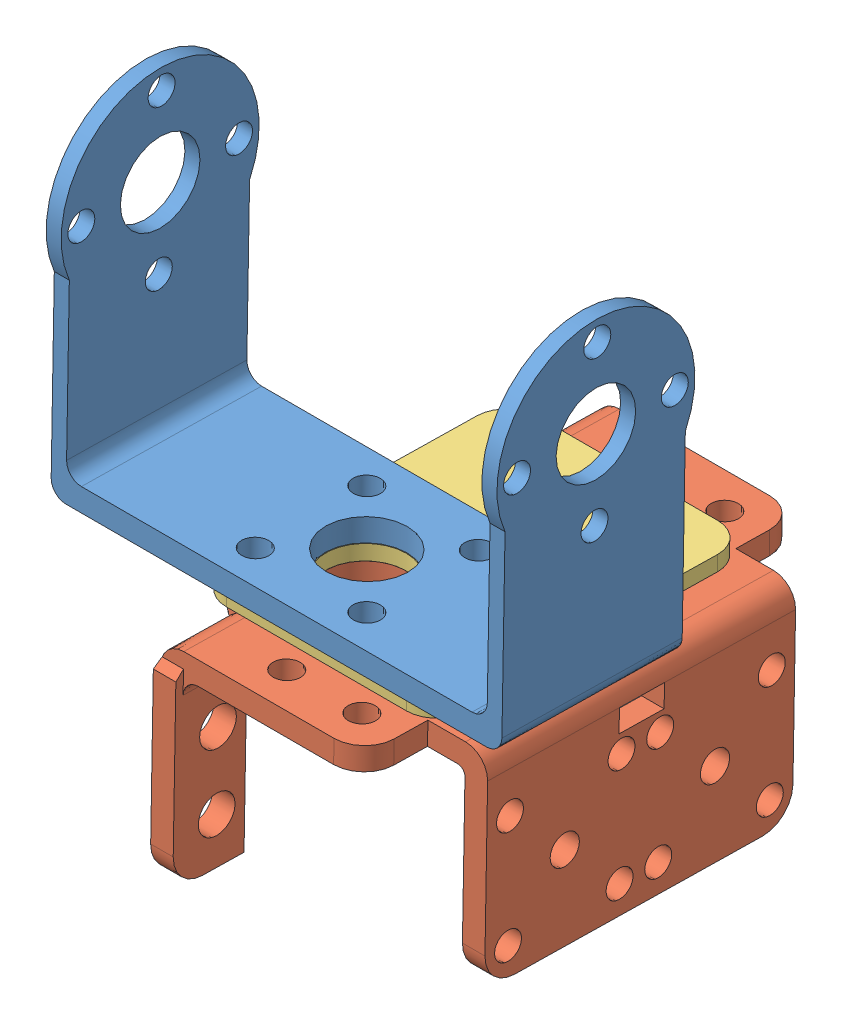
SolidWorks assembly box2_right, configuration Predeterminado. Lengths in mm.
Overall size (60 74.14 60.47).
3 component instances, 3 part files, 6 mates.
Components (placement in the parent):
- u_bracket-1: u_bracket [Predeterminado] at (-18.6428 -64.1261 18.1896) x (1 0 0) z (0 0.017646 0.999844) size (60 44.22 26.36)
- multi_purpose_bracket-3: multi_purpose_bracket [Predeterminado] at (-6.4228 -67.2977 8.4941) x (0 -0.017646 -0.999844) z (-1 0 0) size (60 27 38.5)
- box1_supplement-1: box1_supplement [Predeterminado] at (-14.1428 -67.2944 8.679) x (1 0 0) z (0 0.017646 0.999844) size (32 2 41.37)
Mates (geometry in assembly coordinates):
- Paralelo5: parallel aligned: plane of u_bracket-1 through (-48.6428 -61.9146 30.1524) normal (0 0.017646 0.999844); plane of multi_purpose_bracket-3 through (-3.6728 -69.7854 37.5425) normal (0 0.017646 0.999844)
- Concéntrica1: concentric aligned: cylinder of u_bracket-1 through (-18.6428 -20.9118 17.4269) axis (0 -0.999844 0.017646) radius 5.4; circle of multi_purpose_bracket-3
- Concéntrica2: concentric aligned: cylinder of u_bracket-1 through (-18.6428 -20.9118 17.4269) axis (0 -0.999844 0.017646) radius 5.4; cylinder of multi_purpose_bracket-3 through (-18.6428 -67.1246 18.2425) axis (0 -0.999844 0.017646) radius 5.3
- Concéntrica3: concentric aligned: cylinder of multi_purpose_bracket-3 through (-18.6428 -67.1246 18.2425) axis (0 -0.999844 0.017646) radius 5.3; cylinder of box1_supplement-1 through (-18.6428 -65.1259 18.2073) axis (0 -0.999844 0.017646) radius 5.3
- Coincidente1: coincident anti-aligned: plane of multi_purpose_bracket-3 through (-6.4228 -67.2977 8.4941) normal (0 0.999844 -0.017646); plane of box1_supplement-1 through (-14.1428 -67.2944 8.679) normal (0 -0.999844 0.017646)
- Coincidente2: coincident anti-aligned: plane of u_bracket-1 through (-18.6428 -65.1259 18.2073) normal (0 -0.999844 0.017646); plane of box1_supplement-1 through (-14.1428 -65.2947 8.6437) normal (0 0.999844 -0.017646)
